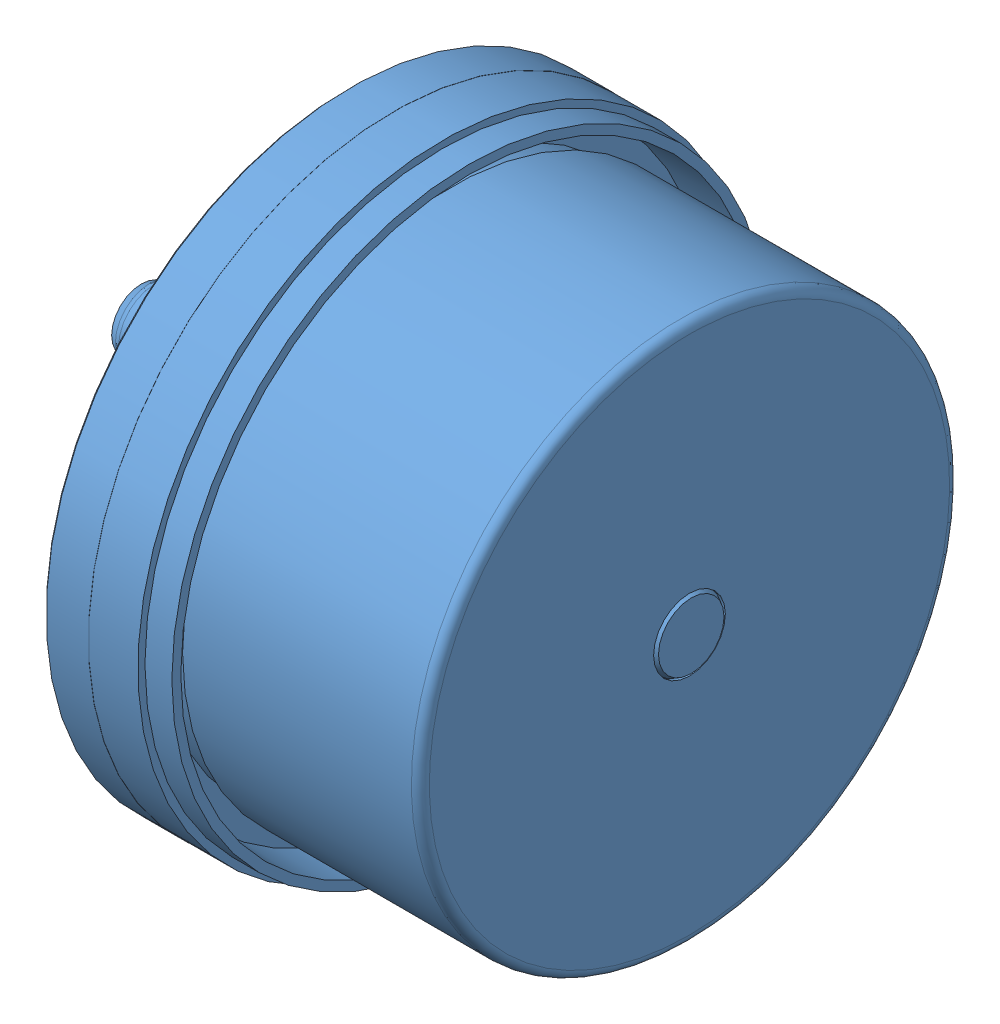
SolidWorks assembly EC60_motor_12_198_IP00, configuration Default. Lengths in mm.
Overall size (61.3 368 68).
7 component instances, 5 part files, 0 mates.
Components (placement in the parent):
- 1393671-1: 1393671 [Default] at origin size (61.3 68 68)
- 1393806_ASM-1: 1393806_ASM [Default] at (7.3675 -28 11.51) x (0 -1 0) z (0 0 -1) size (311 10.85 10.64) (hidden)
  - 1393805-1: 1393805 [Default] at origin size (301 4.37 9.4)
  - 1393804-1: 1393804 [Default] at (296 0 11.43) x (0 0 1) z (0 1 0) size (9.85 14 10.85)
- 1393835_ASM-1: 1393835_ASM [Default] at (10.0675 -245.4 -12.5) x (0 0 -1) z (1 0 0) size (9.68 311 14.4) (hidden)
  - 1393837-1: 1393837 [Default] at origin size (8.17 293.4 6.4)
  - 1393836-1: 1393836 [Default] at (-2.33 -79.7 -1) x (1 0 0) z (0 -1 0) size (9.6 14.4 19.6)
